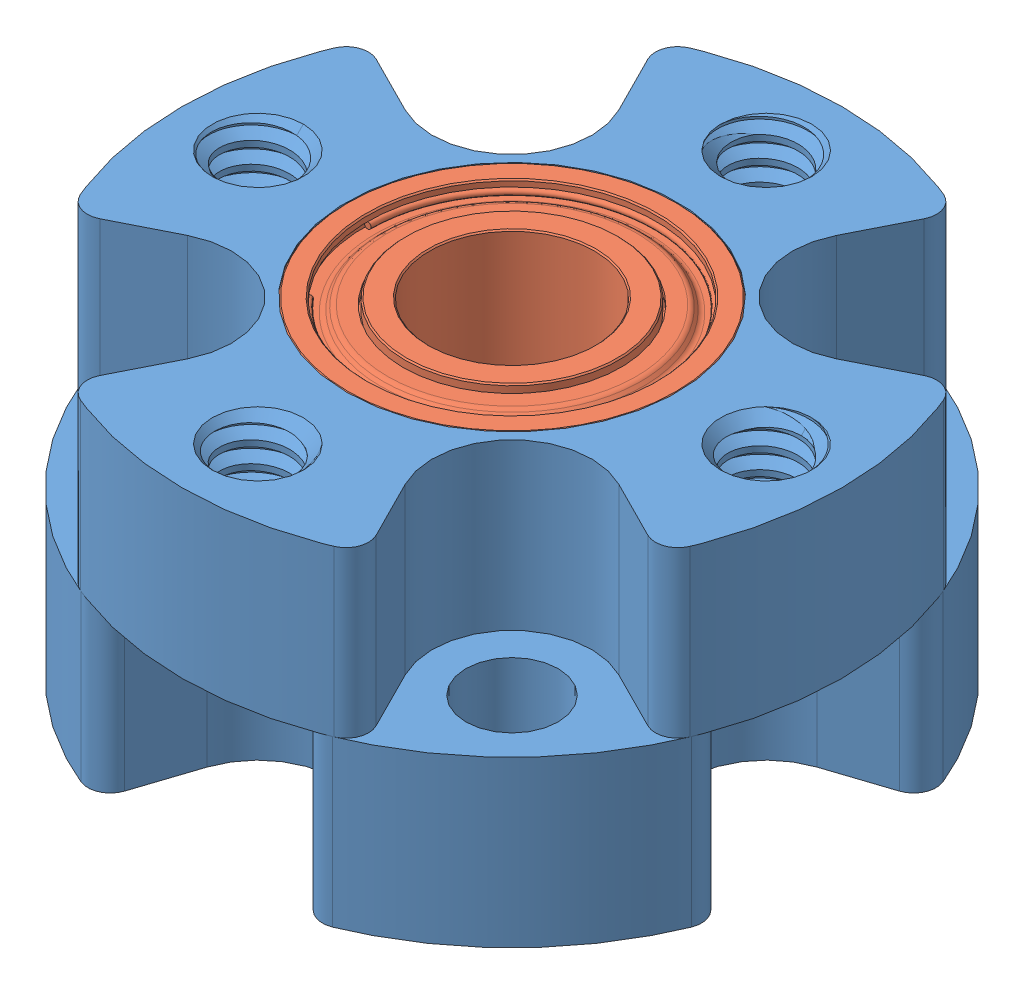
SolidWorks assembly Dual Ball Bearing Hub, configuration Default. Lengths in mm.
Overall size (25.4 12.82 25.4).
3 component instances, 2 part files, 0 mates.
Components (placement in the parent):
- 545444-1: 545444 [Default] at (-30.0172 -12.6196 20.0992) size (25.4 12.82 25.4)
- 535020-1: 535020 [Default] at (-30.0172 -2.3009 20.0992) size (12.7 4.76 12.7)
- 535020-2: 535020 [Default] at (-30.0172 -10.2384 20.0992) x (-0.612569 0 0.790417) z (-0.790417 0 -0.612569) size (12.7 4.76 12.7)
